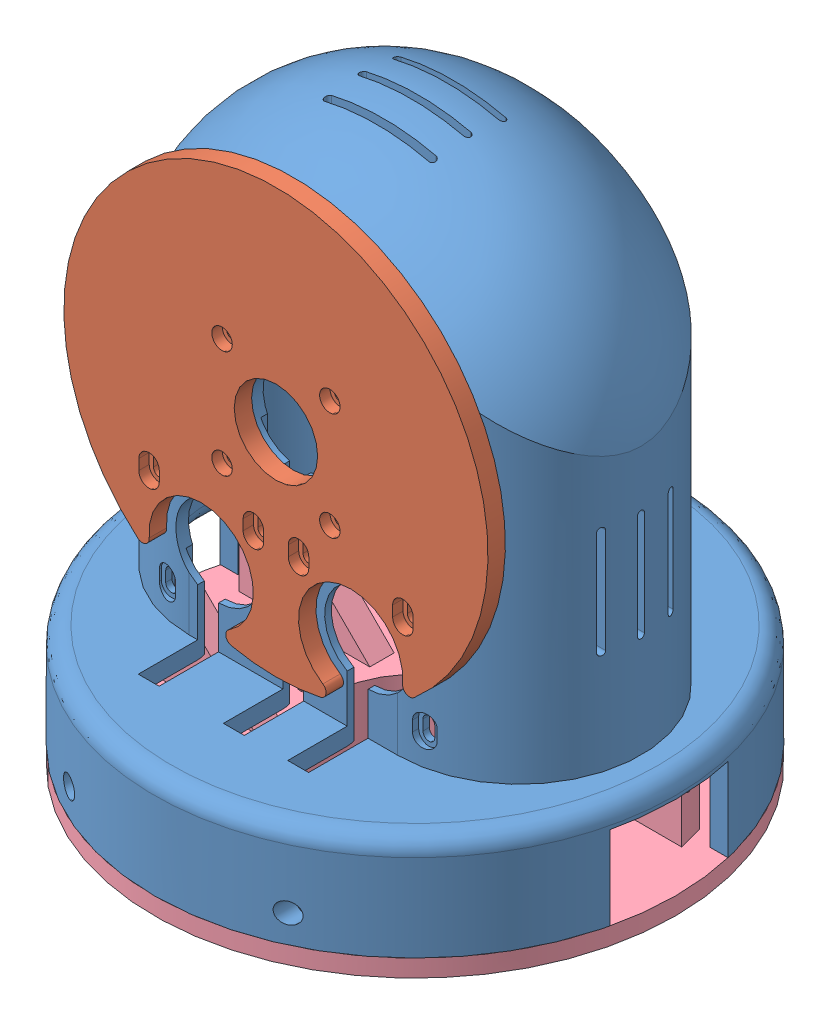
SolidWorks assembly ART1, configuration Predeterminado. Lengths in mm.
Overall size (150 179.49 150).
4 component instances, 4 part files, 62 mates.
Components (placement in the parent):
- Art1Body-1: Art1Body [Predeterminado] at (0.6014 20.889 161.4891) x (1 0 0) z (0 1 0) size (150 150 161.49)
- Art2BodyACover1-1: Art2BodyACover1 [Predeterminado] at (0.6014 118.889 196.4891) x (1 0 0) z (0 -1 0) size (122 5 122)
- AxisFix-1: AxisFix [Predeterminado] at (0.6014 118.889 124.4891) x (0 1 0) z (0 0 -1) size (30 16.4 11)
- Art1Top-1: Art1Top [Predeterminado] at (0.6014 2.889 161.4891) x (0 0 -1) z (1 0 0) size (150 42 150)
Mates (geometry in assembly coordinates):
- Concéntrica4: concentric anti-aligned: cylinder of Art1Body-1 through (0.6014 107.889 136.2975) axis (0 0 -1) radius 1.7; cylinder of hexagon nut_3_jis-1 through (0.6014 107.889 128.4891) axis (0 0 1) radius 1.25
- Paralelo4: parallel aligned: plane of Art1Body-1 through (2.2764 110.7901 128.4891) normal (0 -1 0); plane of hexagon nut_3_jis-1 through (-0.9863 105.139 128.4891) normal (0 -1 0)
- Concéntrica5: concentric anti-aligned: cylinder of Art1Body-1 through (0.6014 118.889 186.4891) axis (0 0 1) radius 12.5; cylinder of Nema17x34Gearbox-1 through (0.6014 118.889 187.6891) axis (0 0 -1) radius 18
- Concéntrica6: concentric aligned: circle of Art1Body-1; circle of Nema17x34Gearbox-1
- Coincidente10: coincident anti-aligned: plane of Art1Body-1 through (0.6014 20.889 192.6891) normal (0 0 -1); plane of Nema17x34Gearbox-1 through (0.6014 118.889 192.6891) normal (0 0 1)
- Concéntrica7: concentric aligned: circle of Art1Body-1; cylinder of Nema17x34Gearbox-3 through (-20.8986 75.589 187.6891) axis (0 0 -1) radius 18
- Concéntrica8: concentric anti-aligned: cylinder of Art1Body-1 through (22.1014 75.589 186.4891) axis (0 0 1) radius 12.5; cylinder of Nema17x34Gearbox-2 through (22.1014 75.589 187.6891) axis (0 0 -1) radius 18
- Paralelo5: parallel aligned: plane of Nema17x34Gearbox-1 through (-20.3986 118.889 73.9922) normal (-1 0 0); plane of Nema17x34Gearbox-3 through (-41.8986 75.589 80.9922) normal (-1 0 0)
- Paralelo6: parallel aligned: plane of Nema17x34Gearbox-2 through (1.1014 75.589 80.9922) normal (-1 0 0); plane of Nema17x34Gearbox-3 through (-41.8986 75.589 80.9922) normal (-1 0 0)
- Coincidente13: coincident anti-aligned: plane of Art1Body-1 through (0.6014 20.889 192.6891) normal (0 0 -1); plane of Nema17x34Gearbox-2 through (22.1014 75.589 192.6891) normal (0 0 1)
- Coincidente14: coincident anti-aligned: plane of Art1Body-1 through (0.6014 20.889 192.6891) normal (0 0 -1); plane of Nema17x34Gearbox-3 through (-20.8986 75.589 192.6891) normal (0 0 1)
- Concéntrica16: concentric anti-aligned: cylinder of Art2MotorGear-2 through (-18.6785 89.0065 204.4898) axis (-0.16324 -0.986586 0) radius 1.7; cylinder of hexagon nut_3_jis-7 through (-20.0137 80.9369 204.4898) axis (0.16324 0.986586 0) radius 1.25
- Concéntrica17: concentric anti-aligned: cylinder of Art2MotorGear-2 through (-18.6785 89.0065 204.4898) axis (-0.16324 -0.986586 0) radius 1.7; cylinder of socket head cap screw_am-2 through (-13.706 119.0595 204.4898) axis (0.16324 0.986586 0) radius 1.5
- Bloquear1: lock: unknown of Art2MotorGear-2; unknown of socket head cap screw_am-2
- Paralelo22: parallel aligned: plane of hexagon nut_3_jis-7 through (-22.7268 81.3858 202.9021) normal (-0.986586 0.16324 0.000013); plane of Art2MotorGear-2 through (-16.837 82.3664 196.1651) normal (-0.986586 0.16324 0.000013)
- Bloquear2: lock: unknown of Art2MotorGear-2; unknown of hexagon nut_3_jis-7
- Concéntrica18: concentric anti-aligned: cylinder of Art2MotorGear-1 through (24.3215 89.0065 204.4891) axis (-0.16324 -0.986586 0) radius 1.7; cylinder of hexagon nut_3_jis-8 through (22.9964 80.9979 204.4891) axis (0.16324 0.986586 0) radius 1.25
- Concéntrica19: concentric anti-aligned: cylinder of Art2MotorGear-1 through (24.3215 89.0065 204.4891) axis (-0.16324 -0.986586 0) radius 1.7; cylinder of socket head cap screw_am-1 through (29.2494 118.7896 204.4891) axis (0.16324 0.986586 0) radius 1.5
- Paralelo24: parallel aligned: plane of Art2MotorGear-1 through (26.163 82.3664 196.1644) normal (-0.986586 0.16324 0.000013); plane of hexagon nut_3_jis-8 through (20.2833 81.4468 202.9015) normal (-0.986586 0.16324 0.000013)
- Bloquear3: lock: unknown of Art2MotorGear-1; unknown of hexagon nut_3_jis-8
- Bloquear4: lock: unknown of Art2MotorGear-1; unknown of socket head cap screw_am-1
- Concéntrica20: concentric aligned: cylinder of Nema17x34Gearbox-2 through (22.1014 75.589 212.6891) axis (0 0 -1) radius 4; cylinder of Art2MotorGear-1 through (22.1014 75.589 225.4891) axis (0 0 -1) radius 3.1
- Concéntrica22: concentric aligned: cylinder of Nema17x34Gearbox-3 through (-20.8986 75.589 212.6891) axis (0 0 -1) radius 4; cylinder of Art2MotorGear-2 through (-20.8986 75.589 225.4898) axis (0 0 -1) radius 3.1
- Concéntrica23: concentric aligned: cylinder of Nema17x34Gearbox-1 through (0.6014 118.889 212.6891) axis (0 0 -1) radius 4; cylinder of GT2_20Teeth_5bore-1 through (0.6014 118.889 212.0435) axis (0 0 -1) radius 2.5
- Concéntrica24: concentric anti-aligned: cylinder of Art1Body-1 through (0.6014 118.889 186.4891) axis (0 0 1) radius 12.5; cylinder of Art2BodyACover1-1 through (0.6014 118.889 201.4891) axis (0 0 -1) radius 12
- Concéntrica25: concentric aligned: cylinder of Art1Body-1 through (-14.8986 134.389 186.4891) axis (0 0 1) radius 1.7; cylinder of Art2BodyACover1-1 through (-14.8986 134.389 196.4891) axis (0 0 1) radius 1.7
- Coincidente39: coincident anti-aligned: plane of Art1Body-1 through (30.6014 182.889 196.4891) normal (0 0 1); plane of Art2BodyACover1-1 through (19.8199 96.5082 196.4891) normal (0 0 -1)
- Concéntrica26: concentric aligned: cylinder of Art1Body-1 through (-14.8986 103.389 186.4891) axis (0 0 1) radius 1.7; cylinder of socket head cap screw_am-5 through (-14.8986 103.389 233.2391) axis (0 0 1) radius 1.5
- Concéntrica27: concentric aligned: circle of Art2BodyACover1-1; cylinder of socket head cap screw_am-3 through (-14.8986 134.389 233.2391) axis (0 0 1) radius 1.5
- Concéntrica29: concentric aligned: cylinder of Art1Body-1 through (16.1014 134.389 186.4891) axis (0 0 1) radius 1.7; cylinder of socket head cap screw_am-6 through (16.1014 134.389 233.2391) axis (0 0 1) radius 1.5
- Concéntrica30: concentric aligned: cylinder of Art1Body-1 through (16.1014 103.389 186.4891) axis (0 0 1) radius 1.7; cylinder of socket head cap screw_am-7 through (16.1014 103.389 233.2391) axis (0 0 1) radius 1.5
- Coincidente40: coincident anti-aligned: plane of Art2BodyACover1-1 through (-14.8986 134.389 198.4891) normal (0 0 1); plane of socket head cap screw_am-3 through (-14.8986 137.139 198.4891) normal (0 0 -1)
- Coincidente41: coincident: line of socket head cap screw_am-5 through (-14.1542 102.1121 201.4891) axis (0.496308 0.868147 0); plane of socket head cap screw_am-7 through (16.1014 103.389 201.4891) normal (0 0 1)
- Coincidente42: coincident aligned: plane of socket head cap screw_am-6 through (16.1014 134.389 201.4891) normal (0 0 1); plane of socket head cap screw_am-7 through (16.1014 103.389 201.4891) normal (0 0 1)
- Coincidente43: coincident aligned: plane of socket head cap screw_am-3 through (-14.8986 134.389 201.4891) normal (0 0 1); plane of socket head cap screw_am-6 through (16.1014 134.389 201.4891) normal (0 0 1)
- Concéntrica31: concentric aligned: circle of Nema17x34Gearbox-3; cylinder of socket head cap screw_am-12 through (-36.3986 60.089 229.2391) axis (0 0 1) radius 1.5
- Concéntrica32: concentric aligned: circle of Nema17x34Gearbox-2; cylinder of socket head cap screw_am-9 through (37.6014 60.089 229.2391) axis (0 0 1) radius 1.5
- Concéntrica33: concentric aligned: circle of Nema17x34Gearbox-3; cylinder of socket head cap screw_am-8 through (-5.3986 91.089 233.2391) axis (0 0 1) radius 1.5
- Concéntrica34: concentric anti-aligned: circle of Nema17x34Gearbox-2; cylinder of socket head cap screw_am-10 through (37.6014 91.089 233.2391) axis (0 0 1) radius 1.5
- Concéntrica35: concentric aligned: cylinder of Nema17x34Gearbox-2 through (6.6014 91.089 167.3891) axis (0 0 1) radius 2.875; cylinder of socket head cap screw_am-11 through (6.6014 91.089 233.2391) axis (0 0 1) radius 1.5
- Concéntrica38: concentric aligned: cylinder of socket head cap screw_am-4 through (-36.3986 91.089 233.2391) axis (0 0 1) radius 1.5; circle of Nema17x34Gearbox-3
- Coincidente44: coincident aligned: plane of socket head cap screw_am-4 through (-36.3986 91.089 201.4891) normal (0 0 1); plane of socket head cap screw_am-8 through (-5.3986 91.089 201.4891) normal (0 0 1)
- Coincidente45: coincident aligned: plane of socket head cap screw_am-8 through (-5.3986 91.089 201.4891) normal (0 0 1); plane of socket head cap screw_am-11 through (6.6014 91.089 201.4891) normal (0 0 1)
- Coincidente46: coincident aligned: plane of socket head cap screw_am-10 through (37.6014 91.089 201.4891) normal (0 0 1); plane of socket head cap screw_am-11 through (6.6014 91.089 201.4891) normal (0 0 1)
- Coincidente47: coincident anti-aligned: plane of Art2BodyACover1-1 through (37.1014 92.589 198.4891) normal (0 0 1); plane of socket head cap screw_am-10 through (34.8971 90.5894 198.4891) normal (0 0 -1)
- Coincidente48: coincident aligned: plane of socket head cap screw_am-9 through (37.6014 60.089 197.4891) normal (0 0 1); plane of socket head cap screw_am-12 through (-36.3986 60.089 197.4891) normal (0 0 1)
- Coincidente49: coincident anti-aligned: plane of Art1Body-1 through (37.6014 58.589 194.4891) normal (0 0 1); plane of socket head cap screw_am-9 through (35.2456 61.5077 194.4891) normal (0 0 -1)
- Concéntrica47: concentric aligned: circle of Nema17x34Gearbox-2; cylinder of socket head cap screw_am-13 through (37.6014 60.089 94.7391) axis (0 0 -1) radius 1.5
- Coincidente56: coincident anti-aligned: plane of Art1Body-1 through (37.6014 61.589 129.4891) normal (0 0 -1); plane of socket head cap screw_am-13 through (40.1416 61.1423 129.4891) normal (0 0 1)
- Concéntrica49: concentric anti-aligned: cylinder of Art1Body-1 through (0.6014 118.889 109.5867) axis (0 0 -1) radius 8.2; cylinder of radial ball bearing_68_skf-1 through (0.6014 118.889 106.3516) axis (0 0 1) radius 2.5
- Coincidente58: coincident anti-aligned: plane of Art1Body-1 through (0.6014 118.889 129.4891) normal (0 0 -1); plane of radial ball bearing_68_skf-1 through (0.6014 121.689 129.4891) normal (0 0 1)
- Concéntrica50: concentric anti-aligned: cylinder of Art1Body-1 through (0.6014 118.889 109.5867) axis (0 0 -1) radius 8.2; cylinder of AxisFix-1 through (0.6014 118.889 120.4891) axis (0 0 1) radius 2.5
- Paralelo26: parallel aligned: plane of Art1Body-1 through (4.0514 138.889 124.4891) normal (-1 0 0); plane of AxisFix-1 through (-2.6486 133.889 120.4891) normal (-1 0 0)
- Coincidente60: coincident anti-aligned: plane of Art1Body-1 through (0.6014 20.889 124.4891) normal (0 0 -1); plane of AxisFix-1 through (0.6014 118.889 124.4891) normal (0 0 1)
- Concéntrica51: concentric aligned: cylinder of socket head cap screw_am-22 through (0.6014 107.889 88.7391) axis (0 0 -1) radius 1.5; cylinder of AxisFix-1 through (0.6014 107.889 123.4891) axis (0 0 -1) radius 2.95
- Concéntrica53: concentric aligned: cylinder of Art1Body-1 through (25.6014 115.3345 193.5402) axis (0 0 -1) radius 1.7; cylinder of Art23Optodisk-1 through (25.6014 115.3345 124.4891) axis (0 0 -1) radius 2.95
- Concéntrica54: concentric aligned: cylinder of Art1Body-1 through (-24.3986 115.3345 193.5402) axis (0 0 -1) radius 1.7; cylinder of Art23Optodisk-1 through (-24.3986 115.3345 124.4891) axis (0 0 -1) radius 2.95
- Coincidente63: coincident anti-aligned: plane of Art1Body-1 through (30.6014 182.889 126.4891) normal (0 0 -1); plane of Art23Optodisk-1 through (0.6014 118.8345 126.4891) normal (0 0 1)
- Coincidente66: coincident aligned: plane of Art2MotorGear-1 through (22.1014 75.589 223.4889) normal (0.000016 0.000016 1); plane of Art2MotorGear-2 through (-20.8986 75.589 223.4896) normal (0.000016 0.000016 1)
- Distancia1: distance = 4 mm anti-aligned: plane of Art2MotorGear-1 through (22.1014 75.589 200.4891) normal (0 0 -1); plane of Art1Body-1 through (30.6014 182.889 196.4891) normal (0 0 1)
- Concéntrica55: concentric: cylinder of Art1Body-1 through (32.1014 28.889 224.4891) axis (0 0 1) radius 2.95; cylinder of Art1Top-1 through (32.1014 28.889 121.4891) axis (0 0 -1) radius 1.7
- Concéntrica56: concentric anti-aligned: cylinder of Art1Body-1 through (0.6014 50.889 161.4891) axis (0 -1 0) radius 75; cylinder of Art1Top-1 through (0.6014 52.5741 161.4891) axis (0 1 0) radius 75
